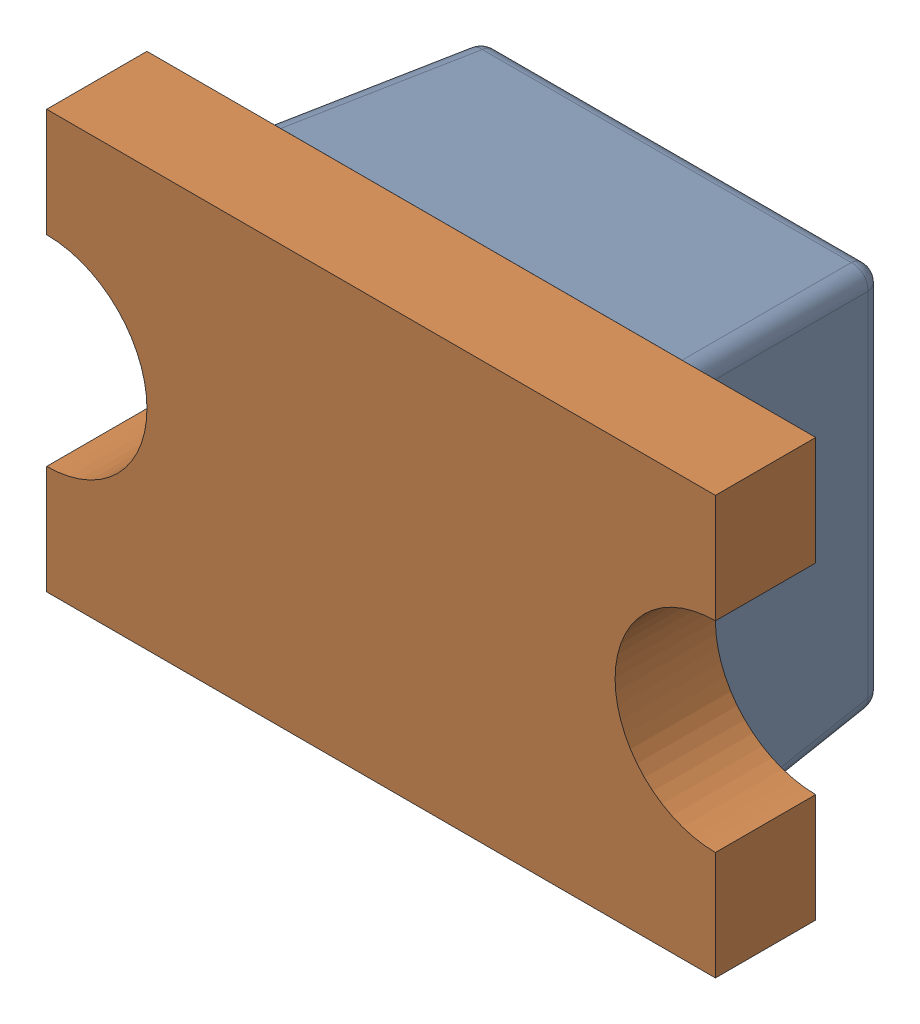
SolidWorks assembly D8, configuration Default. Lengths in mm.
Overall size (2 1.25 0.9).
2 component instances, 2 part files, 0 mates.
Components (placement in the parent):
- LED 0805 Lens RED-1: LED 0805 Lens RED [Default] at (44.8309 95.631 -1.2114) x (-1 0 0) z (0 -1 0) size (1.3 0.6 1.25)
- LED 0805 Base RED-1: LED 0805 Base RED [Default] at (44.8309 95.631 -1.2114) x (-1 0 0) z (0 -1 0) size (2 0.4 1.25)
